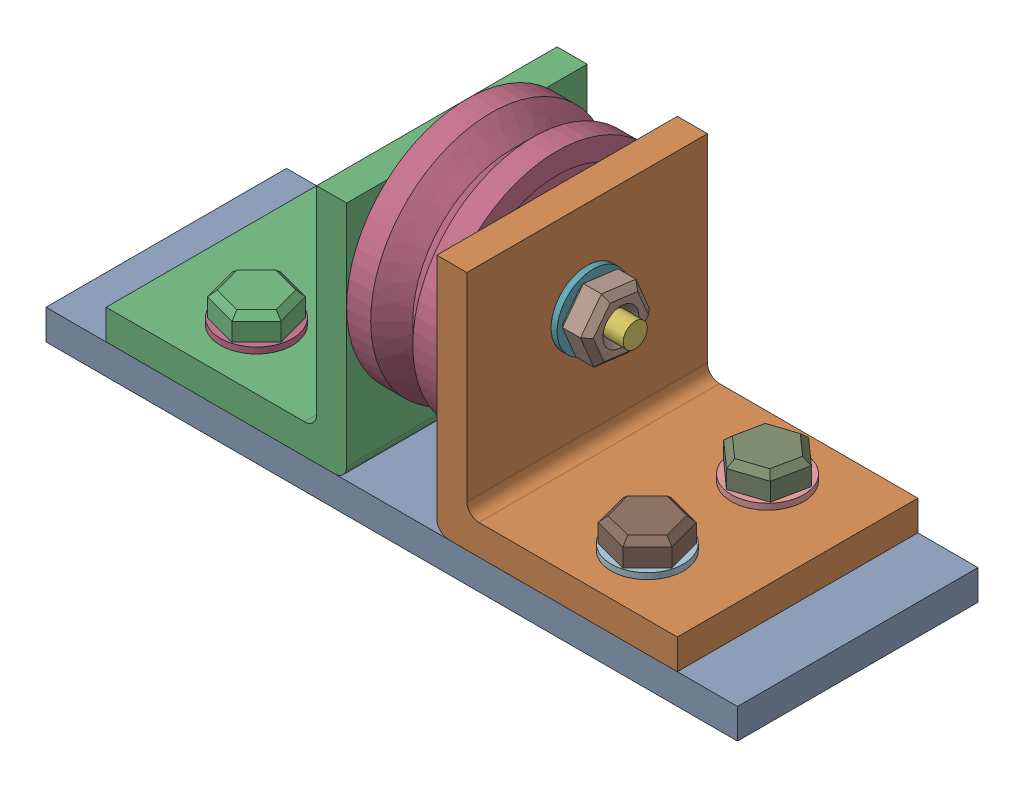
SolidWorks assembly Assem1, configuration Default. Lengths in mm.
Overall size (115 50 40).
16 component instances, 7 part files, 22 mates.
Components (placement in the parent):
- BASE-1: BASE [Default] at (-17.5981 38.5582 -2.3502) size (115 5 40)
- socket-1: socket [Default] at (-10.0981 43.5582 -22.3502) size (40 40 40)
- socket-2: socket [Default] at (-25.0981 43.5582 17.6498) x (-1 0 0) z (0 0 -1) size (40 40 40)
- Pulley-1: Pulley [Default] at (-25.0981 68.5582 -5.7003) size (15 40 40)
- washer1-1: washer1 [Default] at (-30.0981 68.5582 -2.3502) x (0 0 -1) z (-1 0 0) size (12 12 1)
- headsocket-2: headsocket [Default] at (-34.0981 68.5582 -2.3502) x (1 0 0) z (0 0 -1) size (37 10 10)
- washer1-2: washer1 [Default] at (-4.0981 68.5582 -2.3502) x (0 0 1) z (-1 0 0) size (12 12 1)
- bolt-3: bolt [Default] at (-4.4902 30.6605 -5.078) x (0 -0.924225 -0.381849) z (1 0 0) size (11.55 10.03 5)
- nut-1: nut [Default] at (14.9019 49.5582 -12.3502) size (10.96 13 11.31)
- washer1-3: washer1 [Default] at (14.9019 48.5582 -12.3502) x (1 0 0) z (0 1 0) size (12 12 1)
- nut-7: nut [Default] at (14.9019 49.5582 7.6498) x (0.837169 0 0.546944) z (-0.546944 0 0.837169) size (10.96 13 11.31)
- washer1-6: washer1 [Default] at (14.9019 48.5582 7.6498) x (0.837169 0 0.546944) z (0 1 0) size (12 12 1)
- nut-8: nut [Default] at (-50.0981 49.5582 -12.3502) size (10.96 13 11.31)
- washer1-7: washer1 [Default] at (-50.0981 48.5582 -12.3502) x (1 0 0) z (0 1 0) size (12 12 1)
- nut-9: nut [Default] at (-50.0981 49.5582 7.6498) x (0.837169 0 0.546944) z (-0.546944 0 0.837169) size (10.96 13 11.31)
- washer1-8: washer1 [Default] at (-50.0981 48.5582 7.6498) x (0.837169 0 0.546944) z (0 1 0) size (12 12 1)
Mates (geometry in assembly coordinates):
- Coincident3: coincident aligned: circle of BASE-1; circle of socket-1
- Coincident5: coincident aligned: circle of BASE-1; circle of socket-2
- Coincident6: coincident aligned: circle of BASE-1; circle of socket-2
- Coincident7: coincident anti-aligned: circle of socket-1; circle of Pulley-1
- Coincident11: coincident anti-aligned: circle of washer1-1; circle of headsocket-2
- Concentric1: concentric aligned: cylinder of Pulley-1 through (-25.9366 68.5582 -2.3502) axis (-1 0 0) radius 3.125; cylinder of headsocket-2 through (2.9019 68.5582 -2.3502) axis (-1 0 0) radius 3.125
- ProfileCenter3: profile center anti-aligned: plane of washer1-2; circle of socket-1
- Concentric13: concentric aligned: cylinder of headsocket-2 through (2.9019 68.5582 -2.3502) axis (-1 0 0) radius 3.125; cylinder of bolt-3 through (0.5098 68.5582 -2.3502) axis (-1 0 0) radius 2
- Concentric15: concentric anti-aligned: circle of nut-1; circle of washer1-3
- Coincident22: coincident anti-aligned: plane of nut-1 through (14.9019 49.5582 -12.3502) normal (0 -1 0); plane of washer1-3 through (14.9019 49.5582 -12.3502) normal (0 1 0)
- Concentric18: concentric aligned: cylinder of socket-1 through (14.9019 8.5582 -12.3502) axis (0 1 0) radius 2.5; cylinder of nut-1 through (14.9019 40.5582 -12.3502) axis (0 1 0) radius 2.5
- Coincident25: coincident anti-aligned: plane of socket-1 through (-3.0981 48.5582 17.6498) normal (0 1 0); plane of washer1-3 through (14.9019 48.5582 -12.3502) normal (0 -1 0)
- ProfileCenter4: profile center anti-aligned: circle of washer1-6; circle of nut-7
- Concentric20: concentric aligned: cylinder of socket-1 through (14.9019 8.5582 7.6498) axis (0 1 0) radius 2.5; cylinder of nut-7 through (14.9019 40.5582 7.6498) axis (0 1 0) radius 2.5
- Coincident26: coincident anti-aligned: plane of socket-1 through (-3.0981 48.5582 17.6498) normal (0 1 0); plane of washer1-6 through (14.9019 48.5582 7.6498) normal (0 -1 0)
- Concentric21: concentric anti-aligned: circle of nut-8; circle of washer1-7
- Coincident27: coincident anti-aligned: plane of nut-8 through (-50.0981 49.5582 -12.3502) normal (0 -1 0); plane of washer1-7 through (-50.0981 49.5582 -12.3502) normal (0 1 0)
- Concentric22: concentric aligned: cylinder of socket-2 through (-50.0981 8.5582 -12.3502) axis (0 1 0) radius 2.5; cylinder of nut-8 through (-50.0981 40.5582 -12.3502) axis (0 1 0) radius 2.5
- Coincident28: coincident anti-aligned: plane of socket-2 through (-32.0981 48.5582 -22.3502) normal (0 1 0); plane of washer1-7 through (-50.0981 48.5582 -12.3502) normal (0 -1 0)
- ProfileCenter5: profile center anti-aligned: circle of washer1-8; plane of nut-9 through (-50.0981 49.5582 7.6498) normal (0 -1 0)
- Concentric23: concentric aligned: cylinder of socket-2 through (-50.0981 8.5582 7.6498) axis (0 1 0) radius 2.5; cylinder of nut-9 through (-50.0981 40.5582 7.6498) axis (0 1 0) radius 2.5
- Coincident30: coincident aligned: plane of socket-2 through (-32.0981 48.5582 -22.3502) normal (0 1 0); circle of washer1-8
